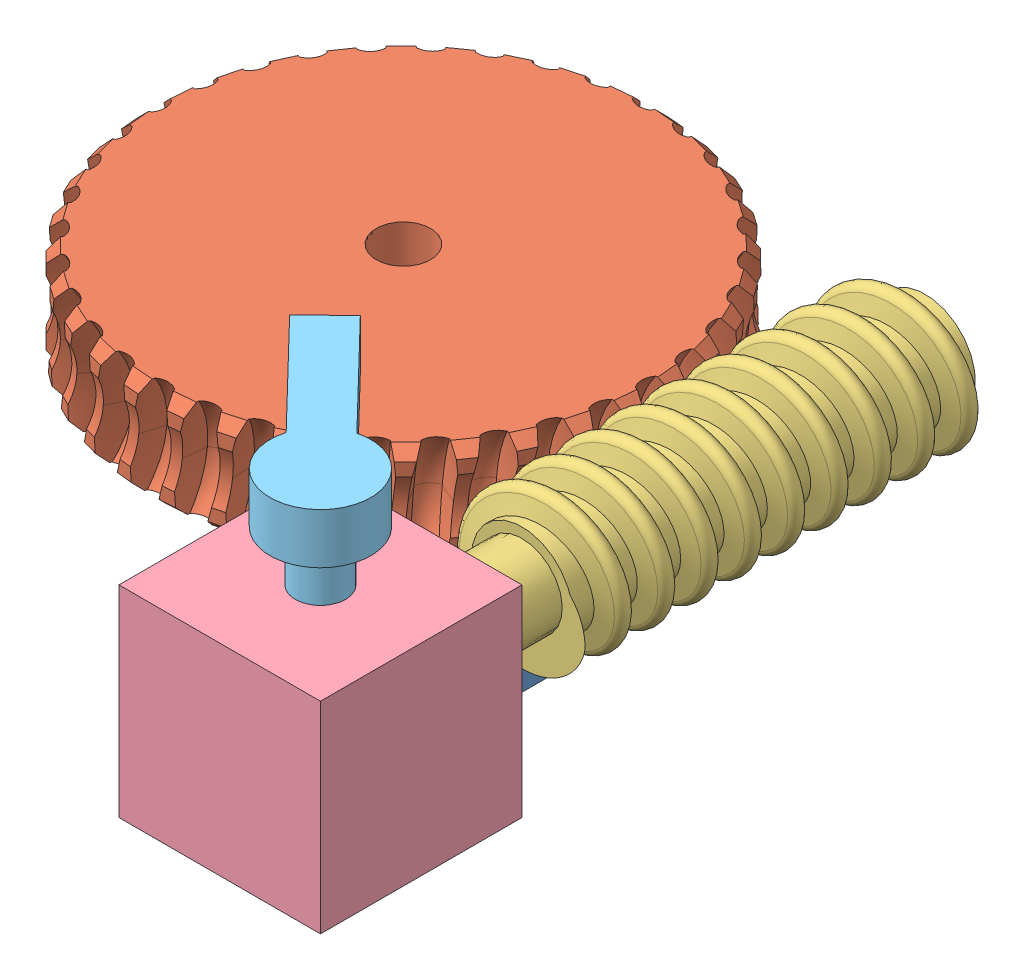
SolidWorks assembly Ball Valve Assembly, configuration Default. Lengths in mm.
Overall size (93.51 66.62 108.76).
6 component instances, 5 part files, 12 mates.
Components (placement in the parent):
- 4114T210_PANEL-MOUNT BRASS BALL VALVE-1: 4114T210_PANEL-MOUNT BRASS BALL VALVE [4114T21] at (18.728 20.1549 38.4089) size (19.05 32.54 46.99)
- Spur Gear-1: Spur Gear [Default] at (18.728 41.4955 38.4089) x (-0.350755 0 0.936467) z (-0.936467 0 -0.350755) size (72.05 17.14 65.35)
- Worm Gear-1: Worm Gear [Default] at (57.4756 50.8117 11.4145) x (0.978271 -0.207329 0) z (0 0 1) size (19.29 19.78 77.18)
- Ground wire_1-Ball Valve Assembly-1: Ground wire_1-Ball Valve Assembly [Default] at origin (suppressed, hidden)
- test piece-1: test piece [Default] at (57.4756 50.8117 100.3145) x (-1 0 0) z (0 0 -1) size (25.4 25.4 25.4)
- test piece 2-1: test piece 2 [Default] at (57.4756 50.8117 87.6145) x (0.719006 0 -0.695004) z (0.695004 0 0.719006) size (12.7 25.4 30.02)
Mates (geometry in assembly coordinates):
- Concentric2: concentric aligned: cylinder of 4114T210_PANEL-MOUNT BRASS BALL VALVE-1 through (18.728 42.1305 38.4089) axis (0 -1 0) radius 6.1274; cylinder of Spur Gear-1 through (18.728 56.7355 38.4089) axis (0 -1 0) radius 3.429
- Coincident1: coincident anti-aligned: plane of 4114T210_PANEL-MOUNT BRASS BALL VALVE-1 through (18.728 42.1305 38.4089) normal (0 1 0); plane of Spur Gear-1 through (18.728 42.1305 38.4089) normal (0 -1 0)
- GearMate3: gear = 10.16 : 279.4 mm: cylinder of Spur Gear-1 through (18.728 56.7355 38.4089) axis (0 -1 0) radius 3.429; cylinder of Worm Gear-1 through (57.4756 50.8117 87.6145) axis (0 0 -1) radius 5.08
- Parallel1: parallel anti-aligned: cylinder of 4114T210_PANEL-MOUNT BRASS BALL VALVE-1 through (18.728 20.1549 14.9129) axis (0 0 1) radius 3.175; cylinder of Worm Gear-1 through (57.4756 50.8117 87.6145) axis (0 0 -1) radius 5.08
- Coincident4: coincident anti-aligned: plane of Worm Gear-1 through (57.4756 50.8117 87.6145) normal (0 0 1); plane of test piece-1 through (57.4756 50.8117 87.6145) normal (0 0 -1)
- Concentric5: concentric aligned: cylinder of Worm Gear-1 through (57.4756 50.8117 87.6145) axis (0 0 -1) radius 5.08; cylinder of test piece-1 through (57.4756 50.8117 87.6145) axis (0 0 -1) radius 3.175
- Distance2: distance = 16.5226 mm anti-aligned: plane of test piece-1 through (44.7756 38.1117 74.9145) normal (-1 0 0); plane of 4114T210_PANEL-MOUNT BRASS BALL VALVE-1 through (28.253 30.4419 29.1506) normal (1 0 0)
- Distance3: distance = 28.2438 mm aligned: plane of test piece-1 through (44.7756 38.1117 74.9145) normal (0 -1 0); plane of 4114T210_PANEL-MOUNT BRASS BALL VALVE-1 through (9.203 9.8679 47.6672) normal (0 -1 0)
- Distance4: distance = 52.6473 mm aligned: plane of test piece-1 through (57.4756 50.8117 100.3145) normal (0 0 1); plane of 4114T210_PANEL-MOUNT BRASS BALL VALVE-1 through (9.203 9.8679 47.6672) normal (0 0 1)
- Coincident10: coincident anti-aligned: plane of test piece-1 through (57.4756 50.8117 87.6145) normal (0 1 0); plane of test piece 2-1 through (57.4756 50.8117 87.6145) normal (0 -1 0)
- Concentric6: concentric anti-aligned: cylinder of test piece-1 through (57.4756 50.8117 87.6145) axis (0 1 0) radius 3.175; cylinder of test piece 2-1 through (57.4756 69.8617 87.6145) axis (0 -1 0) radius 3.175
- GearMate5: gear = 10.16 : 6.35 mm: cylinder of test piece 2-1 through (57.4756 69.8617 87.6145) axis (0 -1 0) radius 3.175; cylinder of Worm Gear-1 through (57.4756 50.8117 87.6145) axis (0 0 -1) radius 5.08
